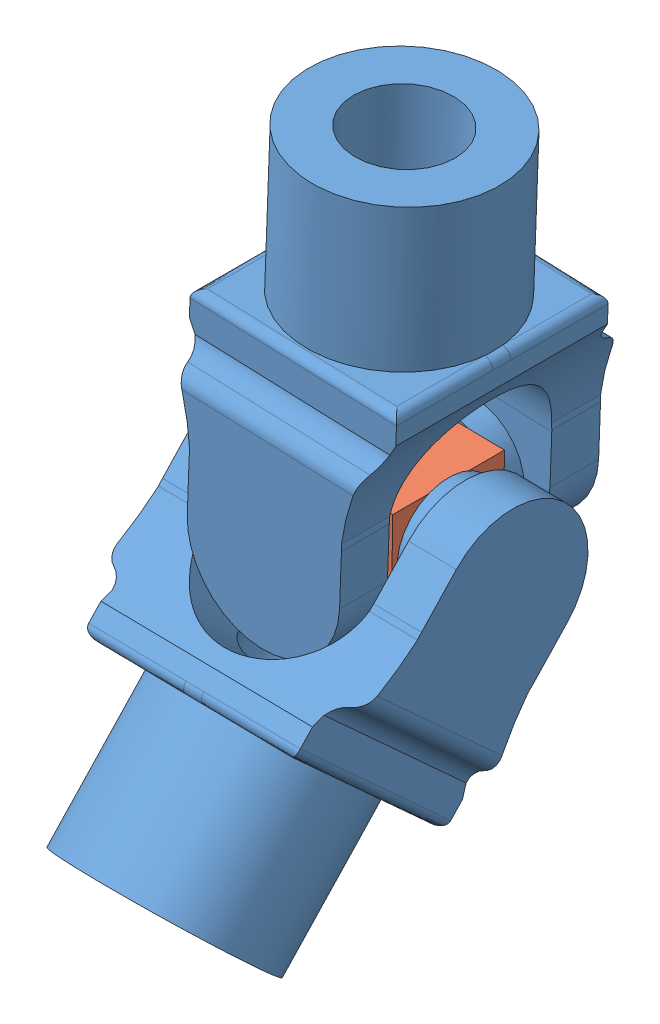
SolidWorks assembly SP22-2100-BASM, configuration Default. Lengths in mm.
Overall size (39.81 97.81 64.52).
3 component instances, 2 part files, 4 mates.
Components (placement in the parent):
- SP22-2101-PRT-1: SP22-2101-PRT [Default] at (30.8215 50.1532 44.2402) x (0.999308 -0.037202 0) z (0 0 1) size (30.99 59.18 38.86)
- SP22-2102-PRT-1: SP22-2102-PRT [Default] at (29.8854 29.2168 44.2402) x (-0.999891 0.014789 0) z (0 0 1) size (21.84 13.97 21.84)
- SP22-2101-PRT-2: SP22-2101-PRT [Default] at (29.4771 1.6094 63.0878) x (0.009977 0.674502 0.738206) z (0.999891 -0.014789 0) size (30.99 59.18 38.86)
Mates (geometry in assembly coordinates):
- Concentric1: concentric aligned: cylinder of steering u joint connector thing-1 through (29.7821 22.2326 55.1622) axis (0 0 -1) radius 3.175; cylinder of steering u joint connector block thing-1 through (29.7821 22.2326 55.1622) axis (0 0 -1) radius 3.175
- Coincident4: coincident anti-aligned: plane of steering u joint connector thing-1 through (29.7821 22.2326 55.1622) normal (0 0 -1); plane of steering u joint connector block thing-1 through (29.7821 22.2326 55.1622) normal (0 0 1)
- Concentric3: concentric aligned: cylinder of steering u joint connector block thing-1 through (40.7029 22.071 44.2402) axis (-0.999891 0.014789 0) radius 3.175; cylinder of steering u joint connector thing-2 through (40.7029 22.071 44.2402) axis (-0.999891 0.014789 0) radius 3.175
- Coincident6: coincident anti-aligned: plane of steering u joint connector block thing-1 through (40.7029 22.071 44.2402) normal (0.999891 -0.014789 0); plane of steering u joint connector thing-2 through (40.7029 22.071 44.2402) normal (-0.999891 0.014789 0)
